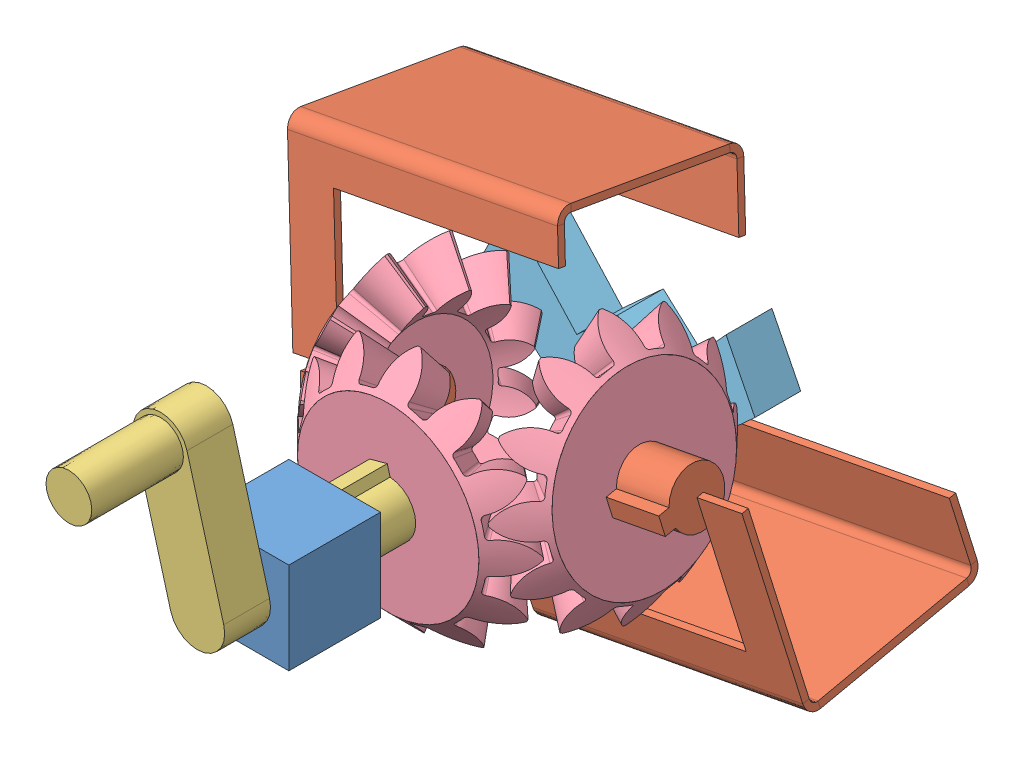
SolidWorks assembly Assembly, configuration Default. Lengths in mm.
Overall size (56.61 41.94 68.14).
8 component instances, 5 part files, 17 mates.
Components (placement in the parent):
- Bushing-1: Bushing [Default] at (5.0173 5.942 11.5065) x (0 1 0) z (0 0 -1) size (10 10 10)
- Claw-1: Claw [Default] at (3.0645 -10.9019 -41.635) x (-0.183232 0.967328 0.175222) z (-0.032611 0.172161 -0.984529) size (23 30 24)
- Claw-2: Claw [Default] at (6.8714 23.3076 -41.2553) x (0.183936 -0.971044 0.152453) z (0.028373 -0.14979 -0.988311) size (23 30 24)
- Handle-1: Handle [Default] at (5.0173 5.942 -8.4935) x (0.963627 0.26725 0) z (0 0 1) size (6 21 35)
- straight miter gear_am-1: straight miter gear_am [Metric - Straight miter gear 2M12T 20PA 5FW ---12O60H10MD6S1] at (18.872 8.5664 -18.44) x (-0.982529 -0.186111 0) z (-0.183232 0.967328 0.175222) size (6.74 26.46 26.46)
- straight miter gear_am-2: straight miter gear_am [Metric - Straight miter gear 2M12T 20PA 5FW ---12O60H10MD6S1] at (5.0173 5.942 -4.339) x (0 0 -1) z (0.963627 0.26725 0) size (6.74 26.46 26.46)
- straight miter gear_am-3: straight miter gear_am [Metric - Straight miter gear 2M12T 20PA 5FW ---12O60H10MD6S1] at (-8.8373 3.3177 -18.44) x (0.982529 0.186111 0) z (0.183936 -0.971044 0.152453) size (6.74 26.46 26.46)
- Item-1: Item [Default] at (-1.226 0.3793 -40.6107) size (30 15 5)
Mates (geometry in assembly coordinates):
- Concentric1: concentric anti-aligned: cylinder of Bushing-1 through (5.0173 5.942 1.5065) axis (0 0 1) radius 2.5; cylinder of Handle-1 through (5.0173 5.942 11.5065) axis (0 0 -1) radius 2.5
- Coincident1: coincident anti-aligned: plane of Bushing-1 through (5.0173 5.942 1.5065) normal (0 0 -1); plane of Handle-1 through (5.0173 5.942 1.5065) normal (0 0 1)
- Concentric2: concentric anti-aligned: cylinder of Handle-1 through (5.0173 5.942 1.5065) axis (0 0 -1) radius 3; cylinder of straight miter gear_am-2 through (5.0173 5.942 -18.44) axis (0 0 1) radius 3
- Coincident2: coincident anti-aligned: plane of Handle-1 through (5.981 6.2093 1.5065) normal (0.963627 0.26725 0); plane of straight miter gear_am-2 through (5.981 6.2093 -18.44) normal (-0.963627 -0.26725 0)
- Coincident3: coincident aligned: plane of Handle-1 through (5.0173 5.942 -8.4935) normal (0 0 -1); plane of straight miter gear_am-2 through (5.0173 5.942 -8.4935) normal (0 0 -1)
- Coincident4: coincident: point of straight miter gear_am-1; point of straight miter gear_am-2
- Coincident5: coincident: point of straight miter gear_am-1; point of straight miter gear_am-3
- Perpendicular1: perpendicular: line of straight miter gear_am-2 through (5.0173 5.942 5.661) axis (0 0 -1); line of straight miter gear_am-3 through (-18.6626 1.4566 -18.44) axis (0.982529 0.186111 0)
- Coincident7: coincident anti-aligned: line of straight miter gear_am-1 through (28.6973 10.4275 -18.44) axis (-0.982529 -0.186111 0); line of straight miter gear_am-3 through (-18.6626 1.4566 -18.44) axis (0.982529 0.186111 0)
- Concentric3: concentric aligned: cylinder of Claw-1 through (14.79 7.7932 -18.44) axis (0.982529 0.186111 0) radius 3; cylinder of straight miter gear_am-1 through (5.0173 5.942 -18.44) axis (0.982529 0.186111 0) radius 3
- Coincident9: coincident anti-aligned: plane of Claw-1 through (14.6721 8.4156 -16.2926) normal (-0.183232 0.967328 0.175222); plane of straight miter gear_am-1 through (4.8341 6.9093 -18.2648) normal (0.183232 -0.967328 -0.175222)
- Coincident10: coincident aligned: plane of Claw-1 through (17.8024 -8.1102 -41.635) normal (-0.982529 -0.186111 0); plane of straight miter gear_am-1 through (14.79 7.7932 -18.44) normal (-0.982529 -0.186111 0)
- Concentric4: concentric aligned: cylinder of Claw-2 through (-4.7553 4.0909 -18.44) axis (-0.982529 -0.186111 0) radius 3; cylinder of straight miter gear_am-3 through (5.0174 5.942 -18.44) axis (-0.982529 -0.186111 0) radius 3
- Coincident11: coincident anti-aligned: plane of Claw-2 through (-4.9961 5.362 -16.6127) normal (-0.183936 0.971044 -0.152453); plane of straight miter gear_am-3 through (4.72 7.5122 -14.6392) normal (0.183936 -0.971044 0.152453)
- Coincident12: coincident aligned: plane of Claw-2 through (-7.8666 20.5159 -41.2553) normal (0.982529 0.186111 0); plane of straight miter gear_am-3 through (-4.7553 4.0909 -18.44) normal (0.982529 0.186111 0)
- GearMate1: gear = 6 : 6 mm: circle of straight miter gear_am-3; circle of straight miter gear_am-2
- GearMate2: gear = 6 : 6 mm: circle of straight miter gear_am-1; circle of straight miter gear_am-2
